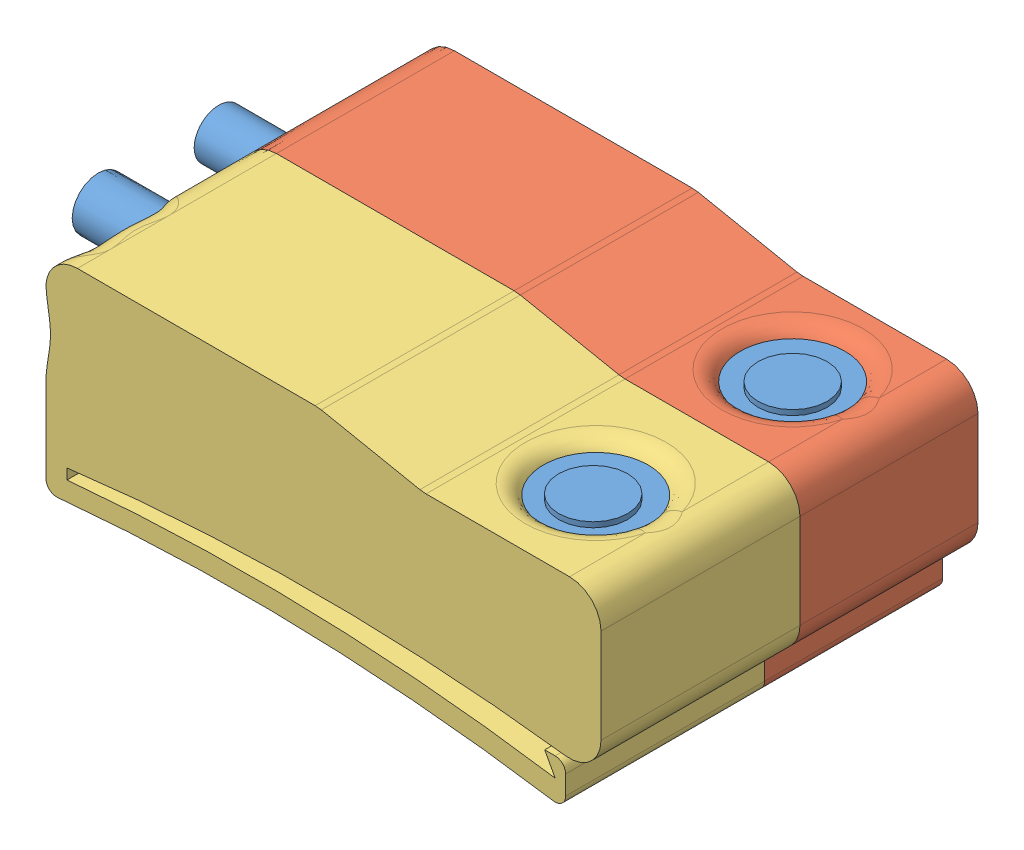
SolidWorks assembly PTT, configuration Standard. Lengths in mm.
Overall size (62 21.33 36.2).
3 component instances, 3 part files, 6 mates.
Components (placement in the parent):
- PTT-1: PTT [Standard] at (-33.1783 1.4396 60) size (60 11.5 31)
- Housing-Right-1: Housing-Right [Standard] at (17.3217 -4.0604 27) size (53 21.33 19)
- Housing-Left-3: Housing-Left [Standard] at (17.3217 -4.0604 61) size (53.58 21.33 19.2)
Mates (geometry in assembly coordinates):
- Deckungsgleich1: coincident anti-aligned: plane of PTT-1 through (-33.1783 2.9396 29) normal (0 0 -1); plane of Housing-Right-1 through (-34.6783 -5.9572 29) normal (0 0 1)
- Deckungsgleich2: coincident anti-aligned: plane of PTT-1 through (15.3217 2.9396 60) normal (1 0 0); plane of Housing-Right-1 through (15.3217 -1.5604 44) normal (-1 0 0)
- Deckungsgleich3: coincident anti-aligned: plane of PTT-1 through (-33.1783 -1.5604 60) normal (0 -1 0); plane of Housing-Right-1 through (-33.6783 -1.5604 44) normal (0 1 0)
- Deckungsgleich4: coincident aligned: plane of Housing-Right-1 through (-35.6783 9.9396 29) normal (-1 0 0); plane of Housing-Left-3 through (-35.6783 9.9396 63) normal (-1 0 0)
- Deckungsgleich5: coincident aligned: plane of Housing-Right-1 through (-9.9754 12.9396 29) normal (0 1 0); plane of Housing-Left-3 through (-9.9754 12.9396 63) normal (0 1 0)
- Deckungsgleich7: coincident anti-aligned: plane of Housing-Right-1 through (-32.6783 9.9396 44) normal (0 0 1); plane of Housing-Left-3 through (-32.6783 9.9396 44) normal (0 0 -1)
